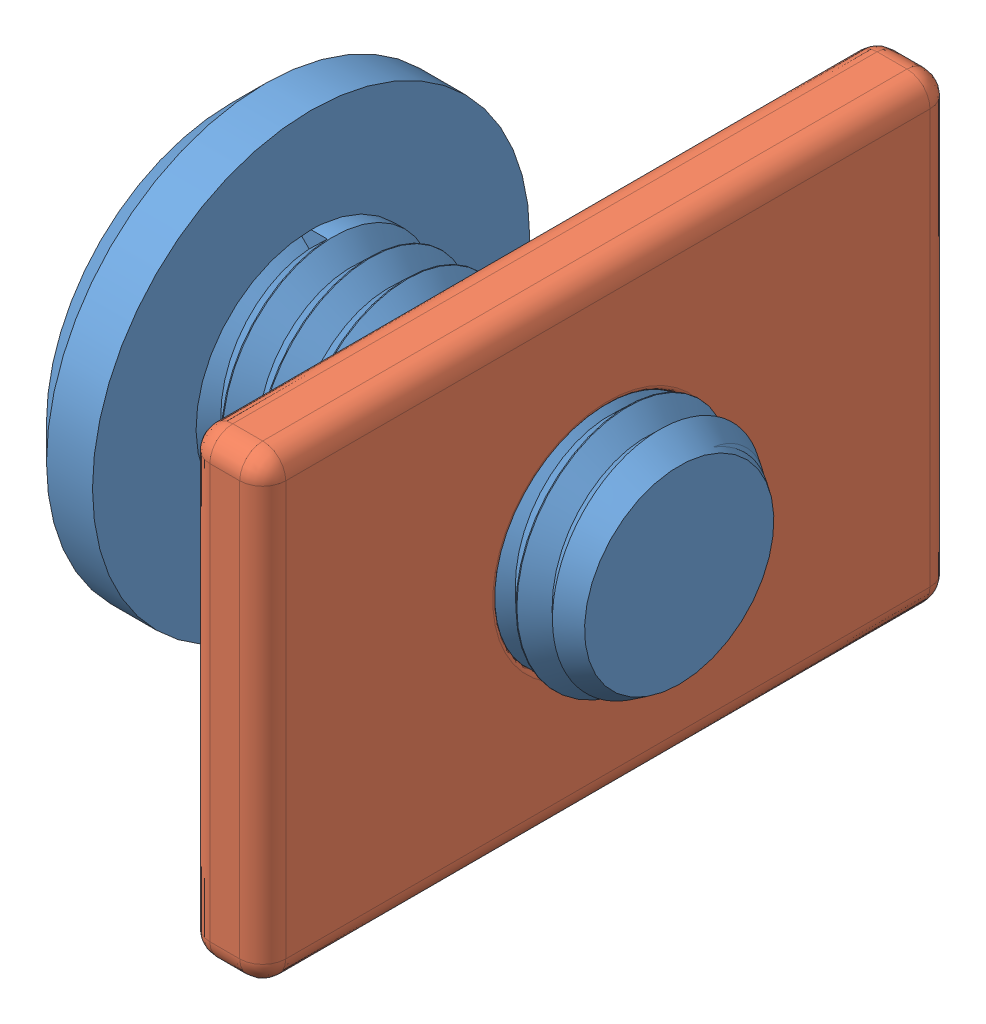
SolidWorks assembly 5mm x 8mm Bolt with Tee Nut, configuration Default. Lengths in mm.
Overall size (10.1 10 15).
2 component instances, 2 part files, 2 mates.
Components (placement in the parent):
- 5mm x 8mm Low Profile Socket Head Screw-1: 5mm x 8mm Low Profile Socket Head Screw [5mm x 8mm Low Profile] at (-34.8438 7.7195 10.4769) size (10.1 9.5 9.5)
- Tee nut-1: Tee nut [Default] at (-28.2938 2.7205 17.9769) x (0 0 -1) z (1 0 0) size (15 10 3.3)
Mates (geometry in assembly coordinates):
- Concentric1: concentric: cylinder of 5mm x 8mm Low Profile Socket Head Screw-1 through (-34.8438 7.7195 10.4769) axis (-1 0 0) radius 4.75; cylinder of Tee nut-1 through (-28.7438 7.7195 10.4769) axis (1 0 0) radius 2.4
- Distance1: distance = 4.8 mm anti-aligned: plane of Tee nut-1 through (-28.2938 2.7205 17.9769) normal (-1 0 0); plane of 5mm x 8mm Low Profile Socket Head Screw-1 through (-33.0938 10.2195 10.4769) normal (1 0 0)
